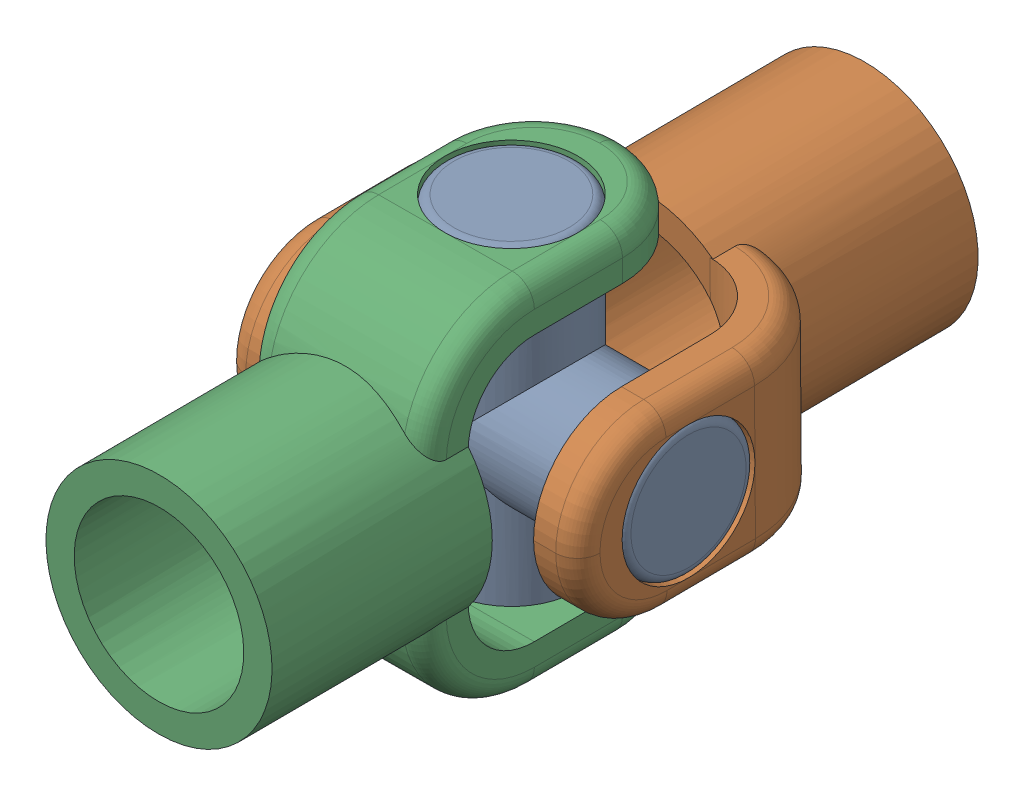
SolidWorks assembly UVJ, configuration Default. Lengths in mm.
Overall size (40 40 80.16).
3 component instances, 2 part files, 4 mates.
Components (placement in the parent):
- CROSS-1: CROSS [Default] at origin size (40 40 15)
- YOKE-1: YOKE [Default] x (1 0 0) z (0 -0.007445 0.999972) size (40 25.4 52.5)
- YOKE-2: YOKE [Default] x (0 1 0) z (-0.005042 0 -0.999987) size (40 25.4 52.5)
Mates (geometry in assembly coordinates):
- Concentric1: concentric anti-aligned: cylinder of CROSS-1 through (20 0 0) axis (-1 0 0) radius 7.5; cylinder of YOKE-1 through (-20 0 0) axis (1 0 0) radius 7.5
- Coincident1: coincident aligned: plane of CROSS-1 through (20 0 0) normal (1 0 0); plane of YOKE-1 through (20 9.9997 0.0744) normal (1 0 0)
- Concentric2: concentric anti-aligned: cylinder of CROSS-1 through (0 20 0) axis (0 -1 0) radius 7.5; cylinder of YOKE-2 through (0 -20 0) axis (0 1 0) radius 7.5
- Coincident2: coincident aligned: plane of CROSS-1 through (0 20 0) normal (0 1 0); plane of YOKE-2 through (9.9999 20 -0.0504) normal (0 1 0)
